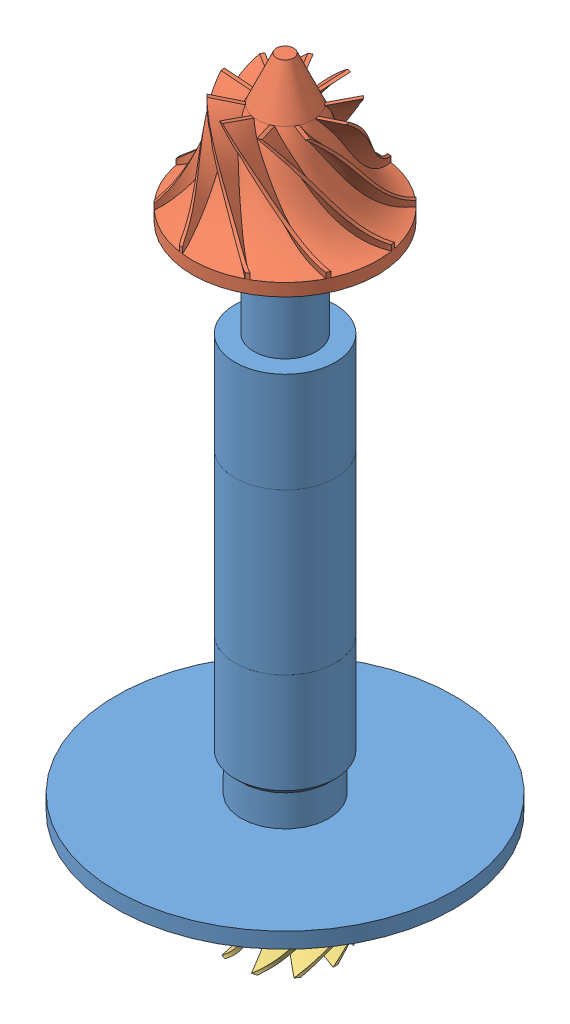
SolidWorks assembly TurboRotor54, configuration Default. Lengths in mm.
Overall size (54 122.53 54).
5 component instances, 5 part files, 9 mates.
Components (placement in the parent):
- 01 Shaft-1: 01 Shaft [Default] at (73.3462 -42.5331 -39.7343) size (54 90.5 54)
- 02 Turbine wheel-1: 02 Turbine wheel [Default] at (73.3462 62.855 -39.7343) x (-0.140485 0 -0.990083) z (0 -1 0) size (30.26 30.26 30.29)
- 03 Compressor-1: 03 Compressor [Default] at (73.3462 -53.5543 -39.7343) x (-0.327276 0 -0.944929) z (0 1 0) size (34.35 34.35 13.74)
- 01_2 Screw1-1: 01_2 Screw1 [Default] at (73.3462 28.5669 -39.7343) x (0 1 0) z (0.335507 0 0.942038) size (17 3.3 3.3)
- 01_03 Screw2-1: 01_03 Screw2 [Default] at (73.3462 -51.1741 -39.7343) x (0 1 0) z (0.072973 0 0.997334) size (16.24 3.3 3.3)
Mates (geometry in assembly coordinates):
- Concentric3: concentric aligned: circle of 02 Turbine wheel-1; cylinder of 01 Shaft-1 through (73.3462 -42.5331 -39.7343) axis (0 -1 0) radius 8
- Coincident1: coincident anti-aligned: plane of 01 Shaft-1 through (78.3462 45.5669 -39.7343) normal (0 1 0); plane of 02 Turbine wheel-1 through (73.3462 45.5669 -39.7343) normal (0 -1 0)
- Concentric4: concentric anti-aligned: circle of 01 Shaft-1; circle of 03 Compressor-1
- Coincident2: coincident anti-aligned: plane of 01 Shaft-1 through (77.3462 -39.9331 -39.7343) normal (0 -1 0); plane of 03 Compressor-1 through (73.3462 -39.9331 -39.7343) normal (0 1 0)
- Concentric5: concentric anti-aligned: circle of 01_2 Screw1-1; cylinder of 01 Shaft-1 through (73.3462 -42.5331 -39.7343) axis (0 -1 0) radius 5
- Concentric6: concentric anti-aligned: circle of 01_03 Screw2-1; cylinder of 01 Shaft-1 through (73.3462 -42.5331 -39.7343) axis (0 -1 0) radius 5
- Coincident3: coincident aligned: plane of 03 Compressor-1 through (73.3462 -51.1741 -39.7343) normal (0 -1 0); plane of 01_03 Screw2-1 through (73.3462 -51.1741 -39.7343) normal (0 -1 0)
- Coincident4: coincident anti-aligned: plane of 02 Turbine wheel-1 through (73.3462 45.5669 -39.7343) normal (0 -1 0); plane of 01_2 Screw1-1 through (73.3462 45.5669 -39.7343) normal (0 1 0)
- Concentric7: concentric aligned: cylinder of 01_2 Screw1-1 through (73.3462 45.5669 -39.7343) axis (0 -1 0) radius 1.65; cylinder of 01 Shaft-1 through (73.3462 -42.5331 -39.7343) axis (0 -1 0) radius 5
